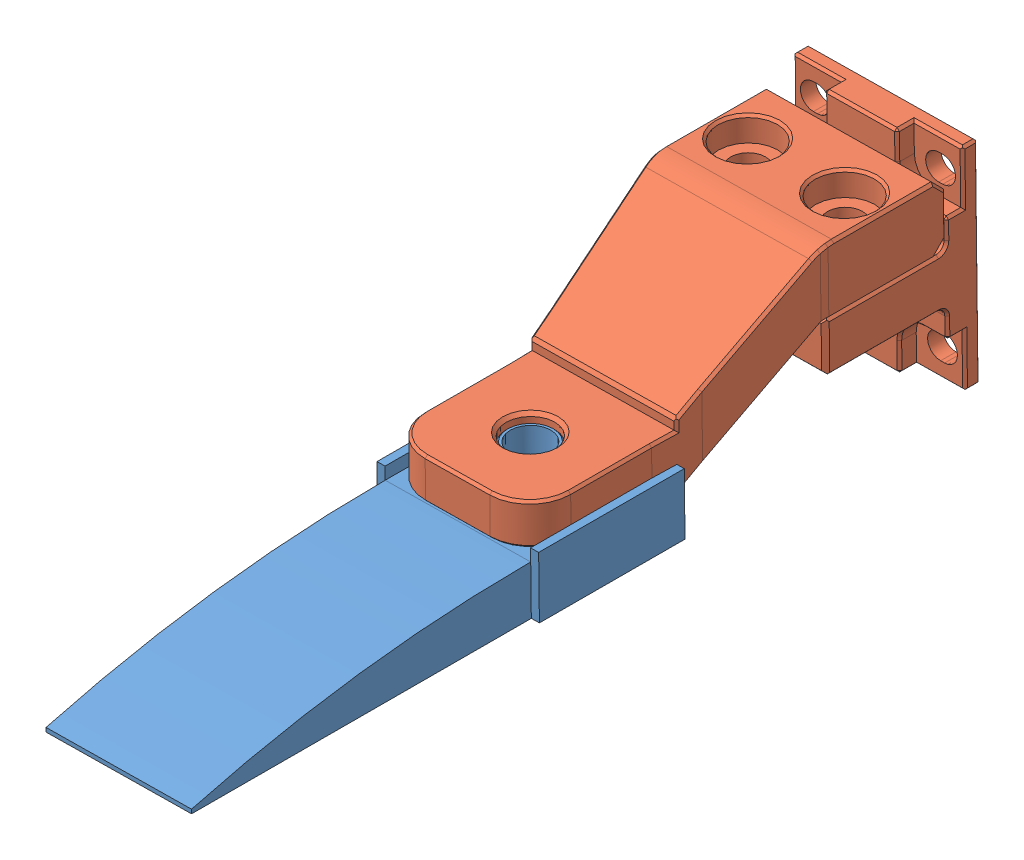
SolidWorks assembly Assem1, configuration Default. Lengths in mm.
Overall size (0.02 0.03 0.1).
3 component instances, 3 part files, 2 mates.
Components (placement in the parent):
- finger-1: finger [Default] at origin size (0.02 0.03 0.05) (hidden)
- panda_adaptor_v2-2: panda_adaptor_v2 [Default] at (-9.0419 3.1365 -6.408) x (0.013795 -0.999904 0.001456) z (0.999905 0.013795 0.00033) size (0.01 0.06 0.02)
- FRANKA_Finger-1: FRANKA_Finger [Standard] at (0.2433 -16.9029 -18.9918) x (0.013795 -0.999904 0.001456) z (-0.000564 0.001449 0.999999) size (0.03 0.02 0.05)
Mates (geometry in assembly coordinates):
- Concentric1: concentric anti-aligned: cylinder of panda_adaptor_v2-2 through (-0.0001 0.0136 0.0451) axis (0.013795 -0.999904 0.001456) radius 0.003; cylinder of FRANKA_Finger-1 through (-0.0001 0.0146 0.0451) axis (-0.013795 0.999904 -0.001456) radius 0.003
- Coincident7: coincident anti-aligned: plane of panda_adaptor_v2-2 through (0.0089 0.0098 0.0541) normal (-0.013795 0.999904 -0.001456); plane of FRANKA_Finger-1 through (0.0104 0.0098 0.0541) normal (0.013795 -0.999904 0.001456)
